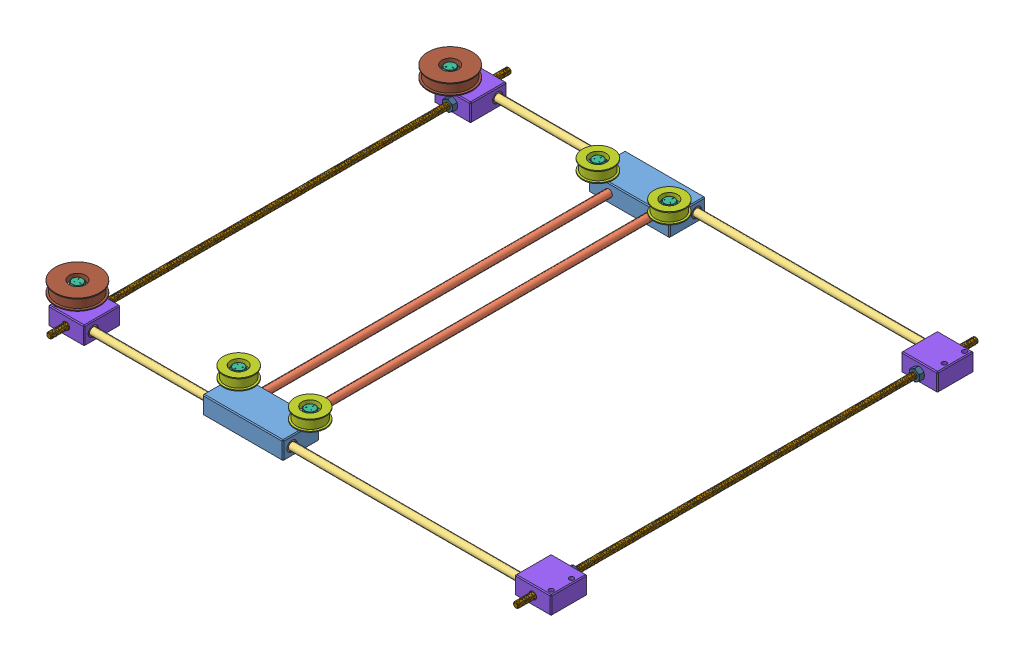
SolidWorks assembly floating gantry, configuration Default. Lengths in mm.
Overall size (584.85 32.66 510.38).
42 component instances, 11 part files, 87 mates.
Components (placement in the parent):
- end_blocks-1: end_blocks [Default] at (-64.3718 11.6319 19.2717) size (88.9 20 40)
- end_blocks-2: end_blocks [Default] at (-64.3718 11.6319 -407.1283) x (-1 0 0) z (0 0 -1) size (88.9 20 40)
- 16in_shaft-1: 16in_shaft [Default] at (-41.8718 21.6319 -397.1283) x (1 0 0) z (0 -1 0) size (8 406.4 8)
- 16in_shaft-2: 16in_shaft [Default] at (-86.8718 21.6319 -397.1283) x (1 0 0) z (0 -1 0) size (8 406.4 8)
- 19.5in_shaft-1: 19.5in_shaft [Default] at (-249.3627 21.6319 29.2717) x (0 -0.118278 0.992981) z (0 0.992981 0.118278) size (8 495.3 8)
- 19.5in_shaft-2: 19.5in_shaft [Default] at (-249.3627 21.6319 -417.1283) x (0 -0.75376 -0.65715) z (0 -0.65715 0.75376) size (8 495.3 8)
- brass_bushing-1: brass_bushing [Default] at (-29.9218 21.6319 29.2717) x (0 -1 0) z (0 0 1) size (11.2 10 11.2)
- brass_bushing-2: brass_bushing [Default] at (-98.8218 21.6319 29.2717) x (0 1 0) z (0 0 1) size (11.2 10 11.2)
- brass_bushing-3: brass_bushing [Default] at (-98.8218 21.6319 -417.1283) x (0 1 0) z (0 0 1) size (11.2 10 11.2)
- brass_bushing-4: brass_bushing [Default] at (-19.9218 21.6319 -417.1283) x (0 1 0) z (0 0 1) size (11.2 10 11.2)
- BALL BEARING-1: BALL BEARING [5972K501] at (-103.8218 35.1319 -392.1283) x (1 0 0) z (0 1 0) size (22 22 7)
- BALL BEARING-2: BALL BEARING [5972K501] at (-24.9218 35.1319 -392.1283) x (1 0 0) z (0 1 0) size (22 22 7)
- BALL BEARING-3: BALL BEARING [5972K501] at (-103.8218 35.1319 4.2717) x (-1 0 0) z (0 1 0) size (22 22 7)
- BALL BEARING-4: BALL BEARING [5972K501] at (-24.9218 35.1319 4.2717) x (1 0 0) z (0 1 0) size (22 22 7)
- Bolt-1: Bolt [92865A542] at (-103.8218 28.1147 -392.1283) x (0 -1 0) z (1 0 0) size (30.4 12.83 11.11)
- Bolt-2: Bolt [92865A542] at (-24.9218 28.1147 -392.1283) x (0 -1 0) z (1 0 0) size (30.4 12.83 11.11)
- Bolt-3: Bolt [92865A542] at (-24.9218 28.1147 4.2717) x (0 -1 0) z (1 0 0) size (30.4 12.83 11.11)
- Bolt-4: Bolt [92865A542] at (-103.8218 28.1147 4.2717) x (0 -1 0) z (-1 0 0) size (30.4 12.83 11.11)
- 30mm_Pulley-1: 30mm_Pulley [Default] at (-24.9218 43.2919 -392.1283) x (0.837169 0 0.546944) z (0.546944 0 -0.837169) size (34 12.66 34)
- 30mm_Pulley-2: 30mm_Pulley [Default] at (-103.8218 43.2919 -392.1283) x (0.837169 0 0.546944) z (0.546944 0 -0.837169) size (34 12.66 34)
- 30mm_Pulley-3: 30mm_Pulley [Default] at (-103.8218 43.2919 4.2717) x (0.837169 0 0.546944) z (0.546944 0 -0.837169) size (34 12.66 34)
- 30mm_Pulley-4: 30mm_Pulley [Default] at (-24.9218 43.2919 4.2717) x (-0.837169 0 -0.546944) z (-0.546944 0 0.837169) size (34 12.66 34)
- corner_block-1: corner_block [Default] at (255.9373 11.6319 -407.1283) size (40 20 40)
- corner_block-2: corner_block [Default] at (-259.3627 31.6319 -407.1283) x (-1 0 0) z (0 0 1) size (40 20 40)
- corner_block-3: corner_block [Default] at (-259.3627 11.6319 19.2717) x (-1 0 0) z (0 0 -1) size (40 20 40)
- corner_block-4: corner_block [Default] at (255.9373 31.6319 19.2717) x (1 0 0) z (0 0 -1) size (40 20 40)
- brass_bushing-5: brass_bushing [Default] at (-249.3627 21.6319 29.2717) x (0 -0.381849 0.924225) z (0 0.924225 0.381849) size (11.2 10 11.2)
- brass_bushing-6: brass_bushing [Default] at (-249.3627 21.6319 -417.1283) x (0 -0.381849 0.924225) z (0 0.924225 0.381849) size (11.2 10 11.2)
- brass_bushing-7: brass_bushing [Default] at (245.9373 21.6319 -417.1283) x (0 1 0) z (0 0 1) size (11.2 10 11.2)
- brass_bushing-8: brass_bushing [Default] at (245.9373 21.6319 29.2717) x (0 1 0) z (0 0 1) size (11.2 10 11.2)
- Threaded_rod_20in-1: Threaded_rod_20in [99065A120] at (255.9373 21.6319 -195.6783) x (0 0 -1) z (0.910773 0.412908 0) size (510.38 6.43 7.33)
- Threaded_rod_20in-2: Threaded_rod_20in [99065A120] at (-259.3627 21.6319 -195.6783) x (0 0 -1) z (0.20061 0.979671 0) size (510.38 6.43 7.33)
- HEX NUT-2: HEX NUT [95505A601] at (-259.3627 21.6319 -384.3502) size (11.11 12.83 7.14)
- HEX NUT-3: HEX NUT [95505A601] at (-259.3627 21.6319 -3.5064) size (11.11 12.83 7.14)
- HEX NUT-6: HEX NUT [95505A601] at (255.9373 21.6319 -384.3502) size (11.11 12.83 7.14)
- HEX NUT-7: HEX NUT [95505A601] at (255.9373 21.6319 -3.5064) size (11.11 12.83 7.14)
- Bolt-5: Bolt [92865A542] at (-274.3627 28.1147 11.7717) x (0 -1 0) z (0 0 1) size (30.4 12.83 11.11)
- BALL BEARING-5: BALL BEARING [5972K501] at (-274.3627 35.1319 11.7717) x (0 0 1) z (0 1 0) size (22 22 7)
- Bolt-6: Bolt [92865A542] at (-274.3627 28.1147 -399.6283) x (0 -1 0) z (0 0 1) size (30.4 12.83 11.11)
- BALL BEARING-6: BALL BEARING [5972K501] at (-274.3627 35.1319 -399.6283) x (0 0 1) z (0 1 0) size (22 22 7)
- 45mm_Pulley-1: 45mm_Pulley [Default] at (-274.3627 43.2919 11.7717) x (-0.75801 0 -0.652243) z (-0.652243 0 0.75801) size (49 12.66 49)
- 45mm_Pulley-2: 45mm_Pulley [Default] at (-274.3627 43.2919 -399.6283) x (0.648677 0 0.761064) z (0.761064 0 -0.648677) size (49 12.66 49)
Mates (geometry in assembly coordinates):
- Concentric1: concentric anti-aligned: cylinder of end_blocks-1 through (-86.8718 21.6319 9.2717) axis (0 0 -1) radius 4; cylinder of end_blocks-2 through (-86.8718 21.6319 -397.1283) axis (0 0 1) radius 4
- Concentric2: concentric anti-aligned: cylinder of end_blocks-1 through (-41.8718 21.6319 9.2717) axis (0 0 -1) radius 4; cylinder of end_blocks-2 through (-41.8718 21.6319 -397.1283) axis (0 0 1) radius 4
- Coincident1: coincident anti-aligned: plane of end_blocks-1 through (-41.8718 21.6319 9.2717) normal (0 0 -1); plane of 16in_shaft-1 through (-41.8718 21.6319 9.2717) normal (0 0 1)
- Concentric3: concentric aligned: cylinder of end_blocks-1 through (-41.8718 21.6319 9.2717) axis (0 0 -1) radius 4; cylinder of 16in_shaft-1 through (-41.8718 21.6319 9.2717) axis (0 0 -1) radius 4
- Coincident2: coincident anti-aligned: plane of end_blocks-2 through (-41.8718 21.6319 -397.1283) normal (0 0 1); plane of 16in_shaft-1 through (-41.8718 21.6319 -397.1283) normal (0 0 -1)
- Coincident3: coincident anti-aligned: plane of end_blocks-1 through (-86.8718 21.6319 9.2717) normal (0 0 -1); plane of 16in_shaft-2 through (-86.8718 21.6319 9.2717) normal (0 0 1)
- Concentric4: concentric aligned: cylinder of end_blocks-1 through (-86.8718 21.6319 9.2717) axis (0 0 -1) radius 4; cylinder of 16in_shaft-2 through (-86.8718 21.6319 9.2717) axis (0 0 -1) radius 4
- Concentric5: concentric anti-aligned: cylinder of end_blocks-1 through (-29.9218 21.6319 29.2717) axis (1 0 0) radius 5.6; cylinder of 19.5in_shaft-1 through (245.9373 21.6319 29.2717) axis (-1 0 0) radius 4
- Concentric6: concentric anti-aligned: cylinder of end_blocks-2 through (-29.9218 21.6319 -417.1283) axis (1 0 0) radius 5.6; cylinder of 19.5in_shaft-2 through (245.9373 21.6319 -417.1283) axis (-1 0 0) radius 4
- Coincident4: coincident aligned: plane of 19.5in_shaft-1 through (245.9373 21.6319 29.2717) normal (1 0 0); plane of 19.5in_shaft-2 through (245.9373 21.6319 -417.1283) normal (1 0 0)
- Concentric7: concentric anti-aligned: cylinder of end_blocks-1 through (-29.9218 21.6319 29.2717) axis (1 0 0) radius 5.6; cylinder of brass_bushing-1 through (-19.9218 21.6319 29.2717) axis (-1 0 0) radius 5.6
- Coincident5: coincident anti-aligned: plane of end_blocks-1 through (-29.9218 21.6319 29.2717) normal (1 0 0); plane of brass_bushing-1 through (-29.9218 21.6319 29.2717) normal (-1 0 0)
- Concentric8: concentric anti-aligned: cylinder of 19.5in_shaft-1 through (245.9373 21.6319 29.2717) axis (-1 0 0) radius 4; cylinder of brass_bushing-2 through (-108.8218 21.6319 29.2717) axis (1 0 0) radius 5.6
- Coincident6: coincident anti-aligned: plane of end_blocks-1 through (-98.8218 21.6319 29.2717) normal (-1 0 0); plane of brass_bushing-2 through (-98.8218 21.6319 29.2717) normal (1 0 0)
- Concentric9: concentric anti-aligned: cylinder of 19.5in_shaft-2 through (245.9373 21.6319 -417.1283) axis (-1 0 0) radius 4; cylinder of brass_bushing-4 through (-29.9218 21.6319 -417.1283) axis (1 0 0) radius 5.6
- Coincident7: coincident anti-aligned: plane of end_blocks-2 through (-29.9218 21.6319 -417.1283) normal (1 0 0); plane of brass_bushing-4 through (-29.9218 21.6319 -417.1283) normal (-1 0 0)
- Concentric10: concentric anti-aligned: cylinder of 19.5in_shaft-2 through (245.9373 21.6319 -417.1283) axis (-1 0 0) radius 4; cylinder of brass_bushing-3 through (-108.8218 21.6319 -417.1283) axis (1 0 0) radius 5.6
- Coincident8: coincident aligned: circle of end_blocks-2; plane of brass_bushing-3 through (-98.8218 21.6319 -417.1283) normal (1 0 0)
- Concentric11: concentric anti-aligned: cylinder of BALL BEARING-1 through (-103.8218 38.6319 -392.1283) axis (0 1 0) radius 4; cylinder of Bolt-1 through (-103.8218 38.6319 -392.1283) axis (0 -1 0) radius 3.175
- Coincident9: coincident anti-aligned: plane of BALL BEARING-1 through (-103.8218 38.6319 -398.969) normal (0 1 0); plane of Bolt-1 through (-98.2655 38.6319 -395.3362) normal (0 -1 0)
- Concentric12: concentric aligned: cylinder of end_blocks-2 through (-103.8218 31.6319 -392.1283) axis (0 1 0) radius 2.5527; cylinder of BALL BEARING-1 through (-103.8218 38.6319 -392.1283) axis (0 1 0) radius 4
- Coincident10: coincident anti-aligned: plane of end_blocks-2 through (-64.3718 31.6319 -407.1283) normal (0 1 0); plane of BALL BEARING-1 through (-103.8218 31.6319 -396.4783) normal (0 -1 0)
- Concentric13: concentric anti-aligned: cylinder of BALL BEARING-2 through (-24.9218 38.6319 -392.1283) axis (0 1 0) radius 4; cylinder of Bolt-2 through (-24.9218 38.6319 -392.1283) axis (0 -1 0) radius 3.175
- Coincident11: coincident anti-aligned: plane of BALL BEARING-2 through (-24.9218 38.6319 -398.969) normal (0 1 0); plane of Bolt-2 through (-19.3655 38.6319 -395.3362) normal (0 -1 0)
- Concentric14: concentric aligned: cylinder of end_blocks-2 through (-24.9218 31.6319 -392.1283) axis (0 1 0) radius 2.5527; cylinder of BALL BEARING-2 through (-24.9218 38.6319 -392.1283) axis (0 1 0) radius 4
- Coincident12: coincident anti-aligned: plane of end_blocks-2 through (-64.3718 31.6319 -407.1283) normal (0 1 0); plane of BALL BEARING-2 through (-24.9218 31.6319 -396.4783) normal (0 -1 0)
- Concentric15: concentric anti-aligned: cylinder of BALL BEARING-3 through (-103.8218 38.6319 4.2717) axis (0 1 0) radius 4; cylinder of Bolt-4 through (-103.8218 38.6319 4.2717) axis (0 -1 0) radius 3.175
- Coincident14: coincident anti-aligned: plane of BALL BEARING-3 through (-103.8218 38.6319 11.1124) normal (0 1 0); plane of Bolt-4 through (-109.378 38.6319 7.4796) normal (0 -1 0)
- Concentric16: concentric aligned: cylinder of end_blocks-1 through (-103.8218 31.6319 4.2717) axis (0 1 0) radius 2.5527; cylinder of BALL BEARING-3 through (-103.8218 38.6319 4.2717) axis (0 1 0) radius 4
- Coincident15: coincident anti-aligned: plane of end_blocks-1 through (-64.3718 31.6319 19.2717) normal (0 1 0); plane of BALL BEARING-3 through (-103.8218 31.6319 8.6217) normal (0 -1 0)
- Concentric17: concentric anti-aligned: cylinder of BALL BEARING-4 through (-24.9218 38.6319 4.2717) axis (0 1 0) radius 4; cylinder of Bolt-3 through (-24.9218 38.6319 4.2717) axis (0 -1 0) radius 3.175
- Coincident16: coincident anti-aligned: plane of BALL BEARING-4 through (-24.9218 38.6319 -2.569) normal (0 1 0); plane of Bolt-3 through (-19.3655 38.6319 1.0638) normal (0 -1 0)
- Concentric18: concentric aligned: cylinder of end_blocks-1 through (-24.9218 31.6319 4.2717) axis (0 1 0) radius 2.5527; cylinder of BALL BEARING-4 through (-24.9218 38.6319 4.2717) axis (0 1 0) radius 4
- Coincident17: coincident anti-aligned: plane of BALL BEARING-4 through (-24.9218 31.6319 -6.3783) normal (0 -1 0); plane of end_blocks-1 through (-64.3718 31.6319 19.2717) normal (0 1 0)
- Concentric19: concentric aligned: cylinder of BALL BEARING-2 through (-24.9218 38.6319 -392.1283) axis (0 1 0) radius 11; cylinder of 30mm_Pulley-1 through (-24.9218 31.6319 -392.1283) axis (0 1 0) radius 11
- Coincident18: coincident anti-aligned: plane of BALL BEARING-2 through (-24.9218 38.6319 -402.7783) normal (0 1 0); plane of 30mm_Pulley-1 through (-12.3642 38.6319 -383.9241) normal (0 -1 0)
- Coincident19: coincident anti-aligned: plane of BALL BEARING-1 through (-103.8218 38.6319 -402.7783) normal (0 1 0); plane of 30mm_Pulley-2 through (-91.2642 38.6319 -383.9241) normal (0 -1 0)
- Concentric20: concentric aligned: cylinder of BALL BEARING-1 through (-103.8218 38.6319 -392.1283) axis (0 1 0) radius 11; cylinder of 30mm_Pulley-2 through (-103.8218 31.6319 -392.1283) axis (0 1 0) radius 11
- Coincident20: coincident anti-aligned: plane of BALL BEARING-4 through (-24.9218 38.6319 -6.3783) normal (0 1 0); plane of 30mm_Pulley-4 through (-37.4793 38.6319 -3.9325) normal (0 -1 0)
- Concentric21: concentric aligned: cylinder of BALL BEARING-4 through (-24.9218 38.6319 4.2717) axis (0 1 0) radius 11; cylinder of 30mm_Pulley-4 through (-24.9218 31.6319 4.2717) axis (0 1 0) radius 11
- Coincident21: coincident anti-aligned: plane of BALL BEARING-3 through (-103.8218 38.6319 14.9217) normal (0 1 0); plane of 30mm_Pulley-3 through (-91.2642 38.6319 12.4759) normal (0 -1 0)
- Concentric22: concentric aligned: cylinder of BALL BEARING-3 through (-103.8218 38.6319 4.2717) axis (0 1 0) radius 11; cylinder of 30mm_Pulley-3 through (-103.8218 31.6319 4.2717) axis (0 1 0) radius 11
- Concentric23: concentric anti-aligned: cylinder of corner_block-4 through (245.9373 21.6319 29.2717) axis (-1 0 0) radius 5.6; cylinder of brass_bushing-8 through (235.9373 21.6319 29.2717) axis (1 0 0) radius 5.6
- Coincident22: coincident anti-aligned: plane of corner_block-4 through (245.9373 21.6319 29.2717) normal (-1 0 0); plane of brass_bushing-8 through (245.9373 21.6319 29.2717) normal (1 0 0)
- Coincident23: coincident anti-aligned: plane of 19.5in_shaft-1 through (245.9373 21.6319 29.2717) normal (1 0 0); plane of corner_block-4 through (245.9373 21.6319 29.2717) normal (-1 0 0)
- Concentric24: concentric anti-aligned: cylinder of 19.5in_shaft-1 through (245.9373 21.6319 29.2717) axis (-1 0 0) radius 4; cylinder of brass_bushing-8 through (235.9373 21.6319 29.2717) axis (1 0 0) radius 3.95
- Coincident25: coincident aligned: plane of end_blocks-1 through (-64.3718 31.6319 19.2717) normal (0 1 0); plane of corner_block-4 through (255.9373 31.6319 19.2717) normal (0 1 0)
- Concentric25: concentric anti-aligned: cylinder of corner_block-1 through (245.9373 21.6319 -417.1283) axis (-1 0 0) radius 5.6; cylinder of brass_bushing-7 through (235.9373 21.6319 -417.1283) axis (1 0 0) radius 5.6
- Coincident26: coincident anti-aligned: plane of corner_block-1 through (245.9373 21.6319 -417.1283) normal (-1 0 0); plane of brass_bushing-7 through (245.9373 21.6319 -417.1283) normal (1 0 0)
- Coincident27: coincident anti-aligned: plane of 19.5in_shaft-2 through (245.9373 21.6319 -417.1283) normal (1 0 0); plane of corner_block-1 through (245.9373 21.6319 -417.1283) normal (-1 0 0)
- Concentric26: concentric anti-aligned: cylinder of 19.5in_shaft-2 through (245.9373 21.6319 -417.1283) axis (-1 0 0) radius 4; cylinder of brass_bushing-7 through (235.9373 21.6319 -417.1283) axis (1 0 0) radius 3.95
- Coincident28: coincident aligned: plane of end_blocks-2 through (-64.3718 31.6319 -407.1283) normal (0 1 0); plane of corner_block-1 through (255.9373 31.6319 -407.1283) normal (0 1 0)
- Concentric27: concentric anti-aligned: cylinder of corner_block-3 through (-249.3627 21.6319 29.2717) axis (1 0 0) radius 5.6; cylinder of brass_bushing-5 through (-239.3627 21.6319 29.2717) axis (-1 0 0) radius 3.95
- Coincident29: coincident anti-aligned: plane of corner_block-3 through (-249.3627 21.6319 29.2717) normal (1 0 0); plane of brass_bushing-5 through (-249.3627 21.6319 29.2717) normal (-1 0 0)
- Coincident30: coincident anti-aligned: plane of 19.5in_shaft-1 through (-249.3627 21.6319 29.2717) normal (-1 0 0); plane of corner_block-3 through (-249.3627 21.6319 29.2717) normal (1 0 0)
- Concentric28: concentric aligned: cylinder of 19.5in_shaft-1 through (245.9373 21.6319 29.2717) axis (-1 0 0) radius 4; cylinder of brass_bushing-5 through (-239.3627 21.6319 29.2717) axis (-1 0 0) radius 3.95
- Coincident31: coincident aligned: plane of end_blocks-1 through (-64.3718 31.6319 19.2717) normal (0 1 0); plane of corner_block-3 through (-259.3627 31.6319 19.2717) normal (0 1 0)
- Concentric29: concentric anti-aligned: cylinder of corner_block-2 through (-249.3627 21.6319 -417.1283) axis (1 0 0) radius 5.6; cylinder of brass_bushing-6 through (-239.3627 21.6319 -417.1283) axis (-1 0 0) radius 3.95
- Coincident32: coincident anti-aligned: circle of corner_block-2; plane of brass_bushing-6 through (-249.3627 21.6319 -417.1283) normal (-1 0 0)
- Coincident33: coincident anti-aligned: plane of 19.5in_shaft-2 through (-249.3627 21.6319 -417.1283) normal (-1 0 0); plane of corner_block-2 through (-249.3627 21.6319 -417.1283) normal (1 0 0)
- Concentric30: concentric aligned: cylinder of 19.5in_shaft-2 through (245.9373 21.6319 -417.1283) axis (-1 0 0) radius 4; cylinder of brass_bushing-6 through (-239.3627 21.6319 -417.1283) axis (-1 0 0) radius 3.95
- Coincident34: coincident aligned: plane of end_blocks-2 through (-64.3718 31.6319 -407.1283) normal (0 1 0); plane of corner_block-2 through (-259.3627 31.6319 -407.1283) normal (0 1 0)
- Concentric31: concentric anti-aligned: cylinder of corner_block-4 through (255.9373 21.6319 -0.7283) axis (0 0 1) radius 4; circle of Threaded_rod_20in-1
- Concentric32: concentric anti-aligned: cylinder of corner_block-2 through (-259.3627 21.6319 -387.1283) axis (0 0 -1) radius 4; circle of Threaded_rod_20in-2
- Concentric34: concentric anti-aligned: circle of Threaded_rod_20in-2; circle of HEX NUT-2
- Coincident36: coincident anti-aligned: plane of corner_block-2 through (-239.3627 11.6319 -387.1283) normal (0 0 1); plane of HEX NUT-2 through (-264.919 24.8398 -387.1283) normal (0 0 -1)
- Concentric35: concentric aligned: circle of Threaded_rod_20in-2; circle of HEX NUT-3
- Coincident37: coincident anti-aligned: plane of corner_block-3 through (-239.3627 31.6319 -0.7283) normal (0 0 -1); plane of HEX NUT-3 through (-264.919 24.8398 -0.7283) normal (0 0 1)
- Distance1: distance = 19.05 mm aligned: plane of corner_block-3 through (-239.3627 31.6319 39.2717) normal (0 0 1); plane of Threaded_rod_20in-2 through (-259.3627 21.6319 58.3217) normal (0 0 1)
- Distance2: distance = 19.05 mm aligned: plane of corner_block-4 through (235.9373 11.6319 39.2717) normal (0 0 1); plane of Threaded_rod_20in-1 through (255.9373 21.6319 58.3217) normal (0 0 1)
- Concentric38: concentric aligned: circle of Threaded_rod_20in-1; circle of HEX NUT-7
- Coincident42: coincident anti-aligned: plane of corner_block-4 through (235.9373 11.6319 -0.7283) normal (0 0 -1); plane of HEX NUT-7 through (250.381 24.8398 -0.7283) normal (0 0 1)
- Coincident43: coincident anti-aligned: plane of corner_block-1 through (235.9373 31.6319 -387.1283) normal (0 0 1); plane of HEX NUT-6 through (250.381 24.8398 -387.1283) normal (0 0 -1)
- Concentric39: concentric anti-aligned: circle of Threaded_rod_20in-1; circle of HEX NUT-6
- LimitDistance2: limit distance = 130.541 mm anti-aligned: plane of end_blocks-2 through (-108.8218 31.6319 -427.1283) normal (-1 0 0); plane of corner_block-2 through (-239.3627 11.6319 -387.1283) normal (1 0 0)
- Concentric41: concentric anti-aligned: circle of Bolt-5; circle of BALL BEARING-5
- Coincident47: coincident anti-aligned: plane of Bolt-5 through (-271.1548 38.6319 17.328) normal (0 -1 0); plane of BALL BEARING-5 through (-267.5221 38.6319 11.7717) normal (0 1 0)
- Concentric43: concentric anti-aligned: circle of Bolt-6; circle of BALL BEARING-6
- Coincident52: coincident anti-aligned: plane of Bolt-6 through (-271.1548 38.6319 -394.072) normal (0 -1 0); plane of BALL BEARING-6 through (-267.5221 38.6319 -399.6283) normal (0 1 0)
- Concentric46: concentric anti-aligned: circle of corner_block-3; circle of Bolt-5
- Coincident53: coincident anti-aligned: plane of corner_block-3 through (-259.3627 31.6319 19.2717) normal (0 1 0); plane of BALL BEARING-5 through (-270.0127 31.6319 11.7717) normal (0 -1 0)
- Concentric47: concentric aligned: circle of corner_block-2; circle of Bolt-6
- Coincident54: coincident anti-aligned: plane of corner_block-2 through (-259.3627 31.6319 -407.1283) normal (0 1 0); plane of BALL BEARING-6 through (-270.0127 31.6319 -399.6283) normal (0 -1 0)
- Concentric48: concentric aligned: cylinder of BALL BEARING-5 through (-274.3627 38.6319 11.7717) axis (0 1 0) radius 11; cylinder of 45mm_Pulley-1 through (-274.3627 31.6319 11.7717) axis (0 1 0) radius 11
- Coincident55: coincident anti-aligned: plane of BALL BEARING-5 through (-263.7127 38.6319 11.7717) normal (0 1 0); plane of 45mm_Pulley-1 through (-291.418 38.6319 -2.9038) normal (0 -1 0)
- Concentric49: concentric aligned: cylinder of BALL BEARING-6 through (-274.3627 38.6319 -399.6283) axis (0 1 0) radius 11; cylinder of 45mm_Pulley-2 through (-274.3627 31.6319 -399.6283) axis (0 1 0) radius 11
- Coincident56: coincident anti-aligned: plane of BALL BEARING-6 through (-263.7127 38.6319 -399.6283) normal (0 1 0); plane of 45mm_Pulley-2 through (-259.7675 38.6319 -382.5044) normal (0 -1 0)
